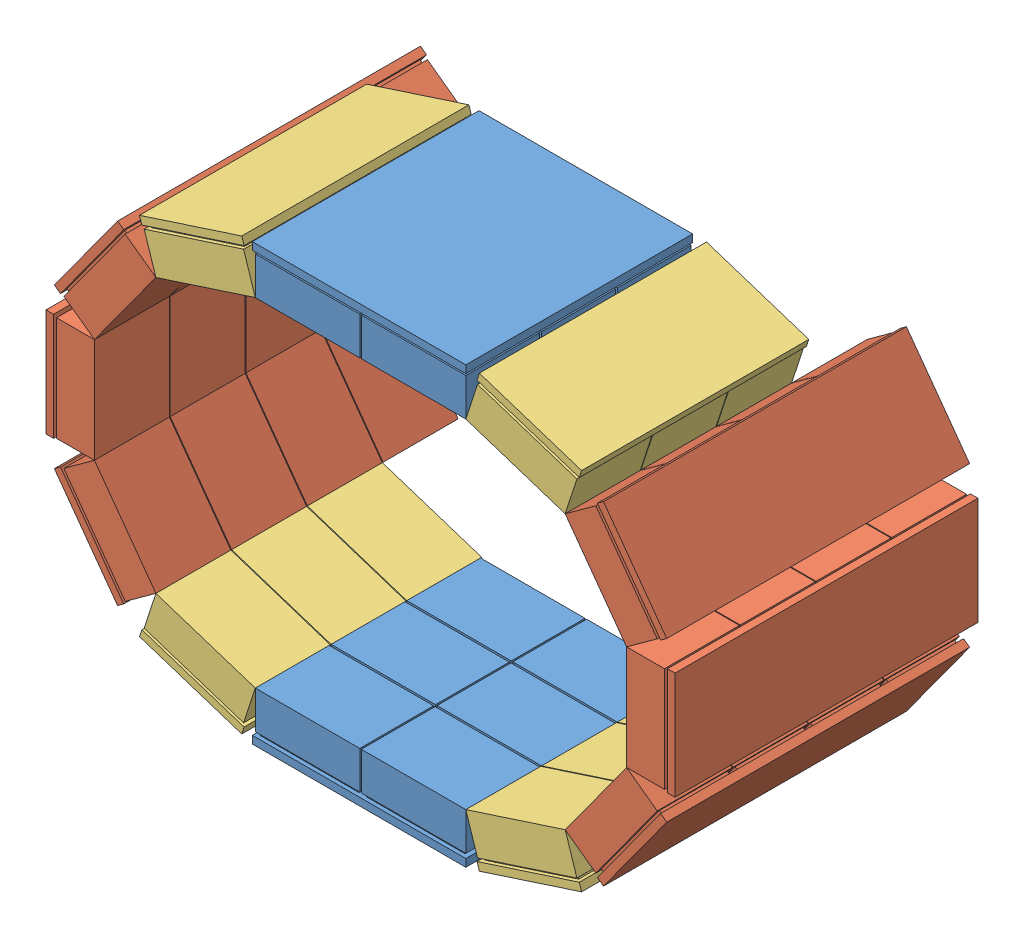
SolidWorks assembly Assem1, configuration Default. Lengths in mm.
Overall size (495.24 340.33 200.99).
14 component instances, 3 part files, 9 mates.
Components (placement in the parent):
- top_bottomDetector2-1: top_bottomDetector2 [Default] at (5.3043 60.2155 74.3483) size (141 32 149.74)
- CshapedDetector2-1: CshapedDetector2 [Default] at (104.3454 -76.5763 -85.899) x (0.951057 0.309017 0) z (0 0 1) size (177.89 270.84 200)
  - 1Detector-2: 1Detector [Default] at (173.0714 153.2337 184.2598) x (0.809017 0.587785 0) z (0 0 1) size (71 32 200)
  - 1Detector-4: 1Detector [Default] at (223.2683 222.3237 184.2598) x (0.309017 0.951057 0) z (0 0 1) size (71 32 200)
  - 1Detector-5: 1Detector [Default] at (223.2683 307.7237 184.2598) x (-0.309017 0.951057 0) z (0 0 1) size (71 32 200)
  - 1Detector_3modules-1: 1Detector_3modules [Default] at (91.8512 126.8436 209.2598) size (71 32 150)
  - 1Detector_3modules-2: 1Detector_3modules [Default] at (173.0714 376.8138 209.2598) x (-0.809017 0.587785 0) z (0 0 1) size (71 32 150)
- CshapedDetector2-2: CshapedDetector2 [Default] at (-23.7368 484.2959 -85.899) x (-0.951057 -0.309017 0) z (0 0 1) size (177.89 270.84 200)
  - 1Detector-2: 1Detector [Default] at (173.0714 153.2337 184.2598) x (0.809017 0.587785 0) z (0 0 1) size (71 32 200)
  - 1Detector-4: 1Detector [Default] at (223.2683 222.3237 184.2598) x (0.309017 0.951057 0) z (0 0 1) size (71 32 200)
  - 1Detector-5: 1Detector [Default] at (223.2683 307.7237 184.2598) x (-0.309017 0.951057 0) z (0 0 1) size (71 32 200)
  - 1Detector_3modules-1: 1Detector_3modules [Default] at (91.8512 126.8436 209.2598) size (71 32 150)
  - 1Detector_3modules-2: 1Detector_3modules [Default] at (173.0714 376.8138 209.2598) x (-0.809017 0.587785 0) z (0 0 1) size (71 32 150)
- top_bottomDetector2-2: top_bottomDetector2 [Default] at (75.3043 347.5042 74.3483) x (-1 0 0) z (0 0 1) size (141 32 149.74)
Mates (geometry in assembly coordinates):
- Coincident2: coincident anti-aligned: line of top_bottomDetector2-1 through (109.8043 92.2155 198.3608) axis (0 0 -1); line of CshapedDetector2-1/1Detector_3modules-1 through (109.8043 92.2155 148.8608) axis (0 0 1)
- Angle1: planar angle = 3.455752 rad anti-aligned: line of top_bottomDetector2-1 through (40.8043 92.2155 198.3608) axis (1 0 0); line of CshapedDetector2-1/1Detector_3modules-1 through (109.8043 92.2155 198.3608) axis (0.951057 0.309017 0)
- Coincident4: coincident: point of top_bottomDetector2-1; point of CshapedDetector2-1/1Detector_3modules-1
- Coincident5: coincident anti-aligned: line of top_bottomDetector2-1 through (-29.1957 92.2155 149.6059) axis (0 0 1); line of CshapedDetector2-2/1Detector_3modules-2 through (-29.1957 92.2155 198.3608) axis (0 0 -1)
- Angle2: planar angle = 3.455752 rad anti-aligned: line of CshapedDetector2-2/1Detector_3modules-2 through (-94.8186 113.5376 198.3608) axis (0.951057 -0.309017 0); line of top_bottomDetector2-1 through (-29.1957 92.2155 198.3608) axis (1 0 0)
- Coincident7: coincident: point of top_bottomDetector2-1; point of CshapedDetector2-2/1Detector_3modules-2
- Coincident8: coincident: line of top_bottomDetector2-2 through (-29.1957 315.5042 198.3608) axis (0 0 -1); line of CshapedDetector2-2/1Detector_3modules-1 through (-29.1957 315.5042 148.8608) axis (0 0 1)
- Coincident11: coincident: line of CshapedDetector2-1/1Detector_3modules-2 through (109.8043 315.5042 198.3608) axis (0 0 -1); line of top_bottomDetector2-2 through (109.8043 315.5042 149.6059) axis (0 0 1)
- Coincident12: coincident: point of CshapedDetector2-2/1Detector_3modules-1; point of top_bottomDetector2-2
